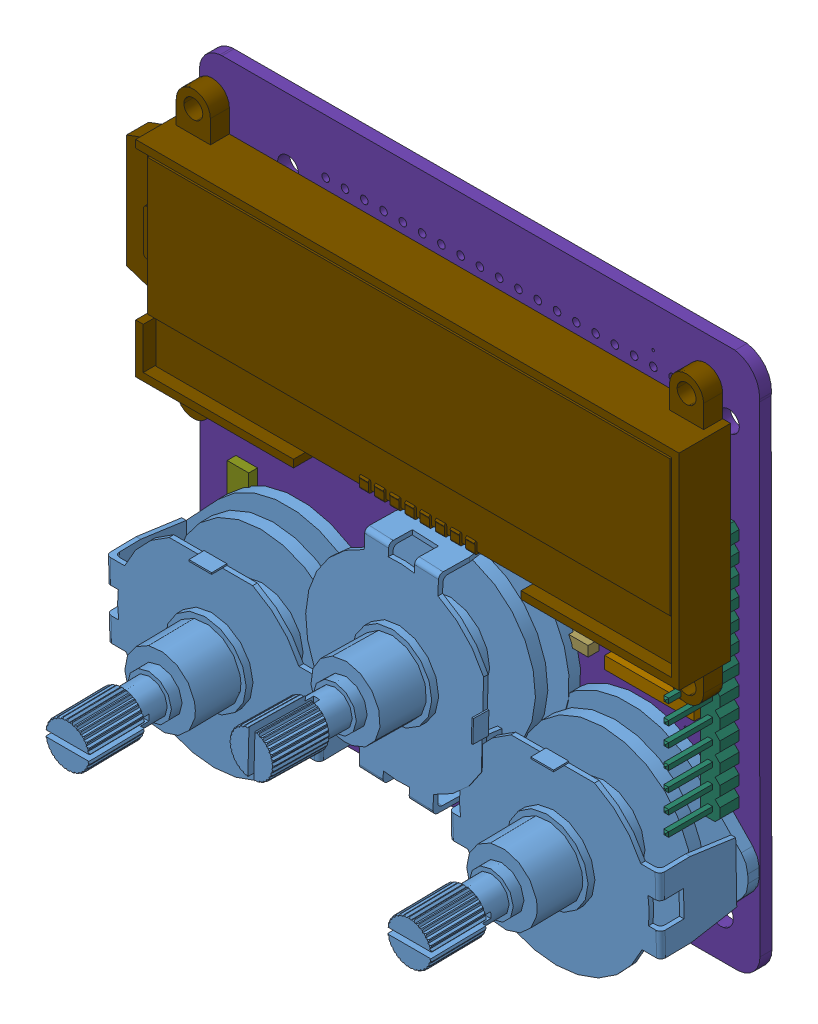
SolidWorks assembly PCB_Height_Sample, configuration Domyślna. Lengths in mm.
Overall size (76.05 71.64 37.03).
31 component instances, 18 part files, 0 mates.
Components (placement in the parent):
- Rotary switch-1: Rotary switch [Default] at (-23.9011 -4.2599 88.3382) x (1 0 0) z (0 0.017452 -0.999848) size (31 25 36.6)
- pcbsample.step-1: pcbsample.step [Domyślna] at (-123.9665 -50.1709 55.5444) size (73.88 70.8 12.37)
  - Packages.step-1: Packages.step [Domyślna] at origin size (68.85 55.12 12.37)
    - DIP254P762X432-18.step-1: DIP254P762X432-18.step [Domyślna] at (148.361 88.9381 1.57) x (0 1 0) z (0 0 1) size (9.32 23.16 0.1)
    - DIP787W46P254L927H533Q8.step-1: DIP787W46P254L927H533Q8.step [Domyślna] at (120.447 85.2043 1.57) x (0 -1 0) z (0 0 1) size (10.31 10.47 0.1)
    - DIP14-2.54-17.24X6.35MM.step-1: DIP14-2.54-17.24X6.35MM.step [Domyślna] at (116.434 70.7517 1.57) x (-1 0 0) z (0 0 1) size (17.5 10.11 0.1)
    - 5V_VOLTAGE_REGULATOR.step-1: 5V_VOLTAGE_REGULATOR.step [Domyślna] at (111.404 42.926 1.57) size (12.83 7.11 0.1)
    - C5B2.5.step-1: C5B2.5.step [Domyślna] at (138.443 66.9163 1.57) x (-1 0 0) z (0 0 1) size (6.68 1.6 0.99)
    - C5B2.5.step-2: C5B2.5.step [Domyślna] at (138.57 71.5391 1.57) x (-1 0 0) z (0 0 1) size (6.68 1.6 0.99)
    - C5B2.5.step-3: C5B2.5.step [Domyślna] at (138.354 75.5269 1.57) size (6.68 1.6 0.99)
    - MA03-1.step-1: MA03-1.step [Domyślna] at (93.0402 85.9155 1.57) size (6.6 3.05 1.84)
    - MA03-1.step-2: MA03-1.step [Domyślna] at (103.251 71.3486 1.57) x (0 1 0) z (0 0 1) size (6.6 3.05 1.84)
    - HC49_S.step-1: HC49_S.step [Domyślna] at (148.323 71.4883 1.57) x (0 1 0) z (0 0 1) size (6.15 1.32 1.44)
    - DO41-10.step-1: DO41-10.step [Domyślna] at (147.091 61.1378 1.57) x (-1 0 0) z (0 0 1) size (11.79 1.63 1.57)
    - LEVEL-SHIFTER-4CH.step-1: LEVEL-SHIFTER-4CH.step [Domyślna] at (105.689 83.6168 1.57) x (0 -1 0) z (0 0 1) size (13.33 13.33 0.1)
    - 0204_7.step-1: 0204_7.step [Domyślna] at (92.5068 43.2562 1.57) x (0 1 0) z (0 0 1) size (8.94 1.32 2.38)
    - 0207_10.step-1: 0207_10.step [Domyślna] at (133.109 61.1505 1.57) x (-1 0 0) z (0 0 1) size (11.48 1.32 1.4)
    - 0207_10.step-2: 0207_10.step [Domyślna] at (152.692 84.5566 1.57) x (0 -1 0) z (0 0 1) size (11.48 1.32 1.4)
    - 0207_10.step-3: 0207_10.step [Domyślna] at (129.222 70.8533 1.57) x (0 -1 0) z (0 0 1) size (11.48 1.32 1.4)
    - 0207_10.step-4: 0207_10.step [Domyślna] at (132.486 70.866 1.57) x (0 -1 0) z (0 0 1) size (11.48 1.32 1.4)
    - 0207_10.step-5: 0207_10.step [Domyślna] at (124.016 58.8264 1.57) x (0 1 0) z (0 0 1) size (11.48 1.32 1.4)
    - 0207_10.step-6: 0207_10.step [Domyślna] at (120.142 58.9661 1.57) x (0 1 0) z (0 0 1) size (11.48 1.32 1.4)
    - 0207_10.step-7: 0207_10.step [Domyślna] at (116.053 59.055 1.57) x (0 -1 0) z (0 0 1) size (11.48 1.32 1.4)
    - JP1.step-1: JP1.step [Domyślna] at (93.0783 68.7324 0) x (0 1 0) z (0 0 -1) size (2.84 3.96 2.26)
    - 1X04.step-1: 1X04.step [Domyślna] at (93.5482 77.7494 1.57) size (10.16 2.54 11.34)
    - 1X13.step-1: 1X13.step [Domyślna] at (156.08 67.7628 1.57) x (0 1 0) z (0 0 1) size (33.02 2.54 11.54)
    - TL3XPO.step-1: TL3XPO.step [Domyślna] at (92.456 55.6514 1.57) x (0 1 0) z (0 0 1) size (6.5 2.84 1.16)
  - Board.step-1: Board.step [Domyślna] at origin size (73.88 70.8 1.57)
- NHD-C0220BiZ-FS_RGB-FBW-3VM.step-1: NHD-C0220BiZ-FS_RGB-FBW-3VM.step [Domyślna] at (-35.1208 22.1136 61.3404) size (75.7 37.6 11)
- Rotary switch-3: Rotary switch [Default] at (21.1524 -4.2599 88.3382) x (1 0 0) z (0 0.017452 -0.999848) size (31 25 36.6)
- Rotary switch-4: Rotary switch [Default] at (0.3294 6.8849 88.3382) x (-0.026177 -0.999657 0) z (0.017446 -0.000457 -0.999848) size (31 25 36.6)
